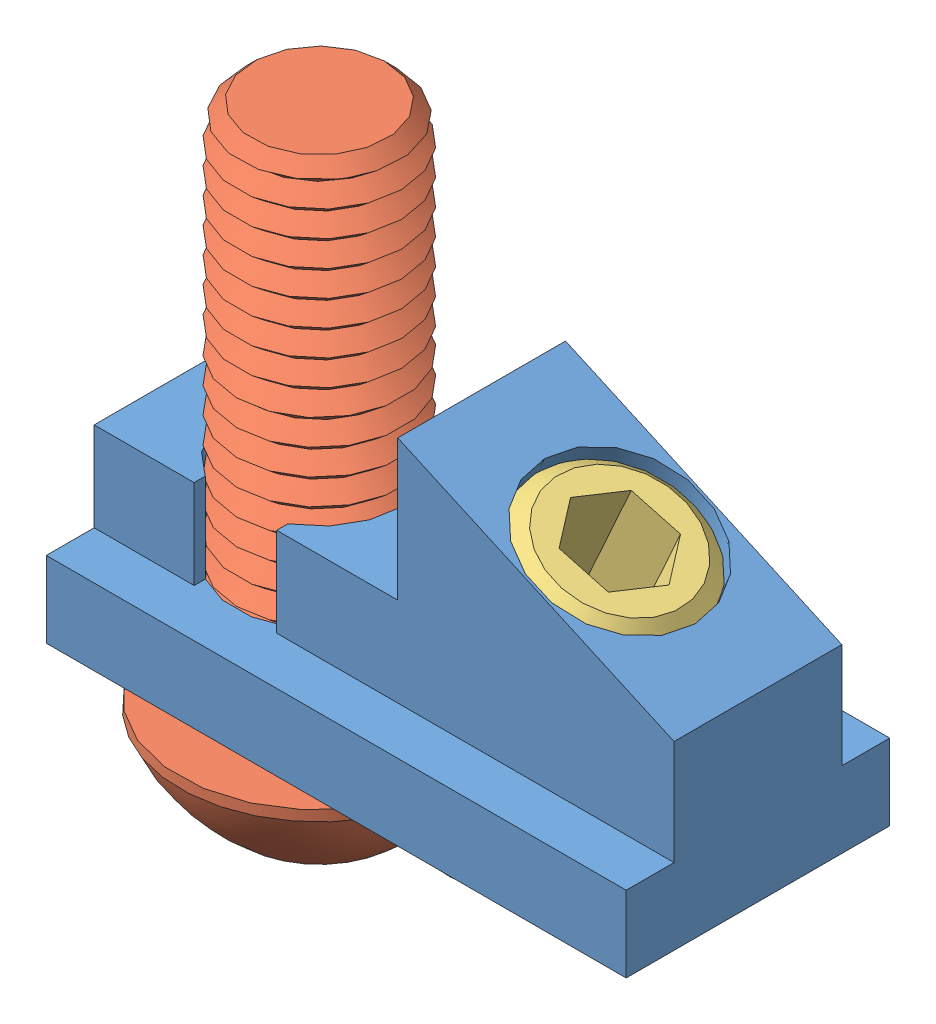
SolidWorks assembly 21.0818 POWER-LOCK SF, configuration Default. Lengths in mm.
Overall size (30.48 29.4 18.46).
3 component instances, 3 part files, 4 mates.
Components (placement in the parent):
- 21.1018 POWER-LOCK BODY-1: 21.1018 POWER-LOCK BODY [Default] at origin size (28.09 14.81 12.77)
- 21.1492 POWER-LOCK SF TORX SCREW-1: 21.1492 POWER-LOCK SF TORX SCREW [Default] at (-7.2022 -2 0) x (-0.864303 0 -0.502971) z (-0.502971 0 0.864303) size (13.5 29.4 13.5)
- 21.1301 M8X16 SET SCREW FLAT DIN 913-1: 21.1301 M8X16 SET SCREW FLAT DIN 913 [Default] at (0.7679 -2.7963 0) x (0.411587 0.911371 0) z (0.117457 -0.053045 0.99166) size (16 8 8)
Mates (geometry in assembly coordinates):
- Concentric1: concentric: circle of 21.1492 POWER-LOCK SF TORX SCREW-1; circle of 21.1018 POWER-LOCK BODY-1
- Distance1: distance = 2 mm: plane of 21.1018 POWER-LOCK BODY-1 through (-14.0462 0 0) normal (0 -1 0); plane of 21.1492 POWER-LOCK SF TORX SCREW-1 through (-4.2852 -2 1.6975) normal (0 1 0)
- Concentric2: concentric: circle of 21.1018 POWER-LOCK BODY-1; circle of 21.1301 M8X16 SET SCREW FLAT DIN 913-1
- Coincident4: coincident: plane of 21.1018 POWER-LOCK BODY-1 through (14.0462 8.763 0) normal (0.411587 0.911371 0); plane of 21.1301 M8X16 SET SCREW FLAT DIN 913-1 through (7.3533 11.7856 0) normal (0.411587 0.911371 0)
